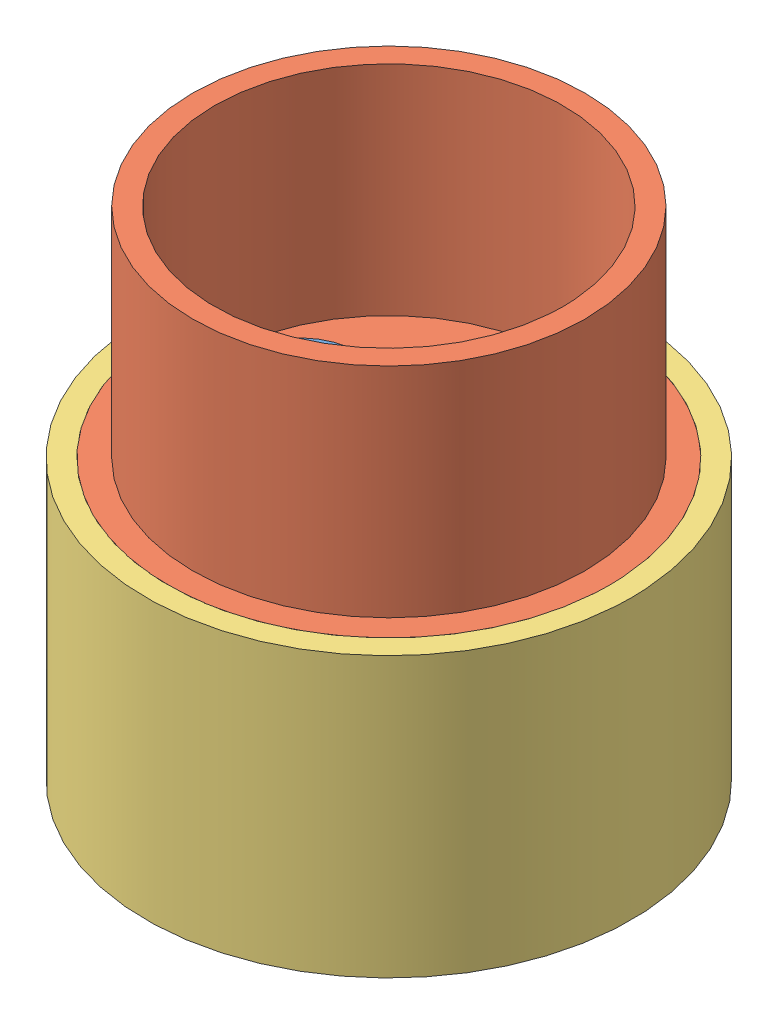
SolidWorks assembly Assem1, configuration Default. Lengths in mm.
Overall size (66.72 68.4 66.72).
3 component instances, 3 part files, 8 mates.
Components (placement in the parent):
- Sonar HC-SR04-1: Sonar HC-SR04 [Default] at (40.7033 19.2431 41.905) size (45.5 18.5 26)
- Part2-1: Part2 [Default] at (40.7033 21.2431 41.905) x (1 0 0) z (0 1 0) size (60.72 60.72 40)
- Part3-1: Part3 [Default] at (40.7033 21.2431 41.905) x (-1 0 0) z (0 -1 0) size (66.72 66.72 38.4)
Mates (geometry in assembly coordinates):
- InPlace2: in place: plane of Sonar HC-SR04-1 through (40.7033 21.2431 41.905) normal (0 1 0); plane of ? through (0 21.2431 0) normal (0 1 0); moOrthogonalPlaneRef_w of Sonar HC-SR04-1 through (40.7033 21.2431 41.905) normal (0 1 0); plane of ? through (0 21.2431 0) normal (0 0 -1); plane of Sonar HC-SR04-1 through (40.7033 21.2431 41.905) normal (0 1 0); plane of ? through (0 21.2431 0) normal (1 0 0); plane of Sonar HC-SR04-1 through (40.7033 21.2431 41.905) normal (0 1 0); unknown of Part2-1
- Coincident4: coincident: plane of Sonar HC-SR04-1; plane of Part2-1
- Coincident5: coincident: moOrthogonalPlaneRef_w of Sonar HC-SR04-1 through (40.7033 21.2431 41.905) normal (0 0 -1); plane of Part2-1 through (40.7033 21.2431 41.905) normal (0 0 -1)
- Coincident6: coincident: moOrthogonalPlaneRef_w of Sonar HC-SR04-1 through (40.7033 21.2431 41.905) normal (-1 0 0); plane of Part2-1 through (40.7033 21.2431 41.905) normal (1 0 0)
- InPlace3: in place: plane of Part2-1 through (40.7033 21.2431 41.905) normal (0 -1 0); plane of ? through (0 21.2431 0) normal (0 -1 0); plane of Part2-1 through (40.7033 21.2431 41.905) normal (0 -1 0); plane of ? through (0 21.2431 0) normal (0 0 -1); plane of Part2-1 through (40.7033 21.2431 41.905) normal (0 -1 0); plane of ? through (0 21.2431 0) normal (-1 0 0); plane of Part2-1 through (40.7033 21.2431 41.905) normal (0 -1 0); unknown of Part3-1
- Coincident7: coincident: plane of Part2-1; plane of Part3-1
- Coincident8: coincident: moOrthogonalPlaneRef_w of Part2-1 through (40.7033 21.2431 41.905) normal (0 0 -1); plane of Part3-1 through (40.7033 21.2431 41.905) normal (0 0 -1)
- Coincident9: coincident: moOrthogonalPlaneRef_w of Part2-1 through (40.7033 21.2431 41.905) normal (1 0 0); plane of Part3-1 through (40.7033 21.2431 41.905) normal (-1 0 0)
